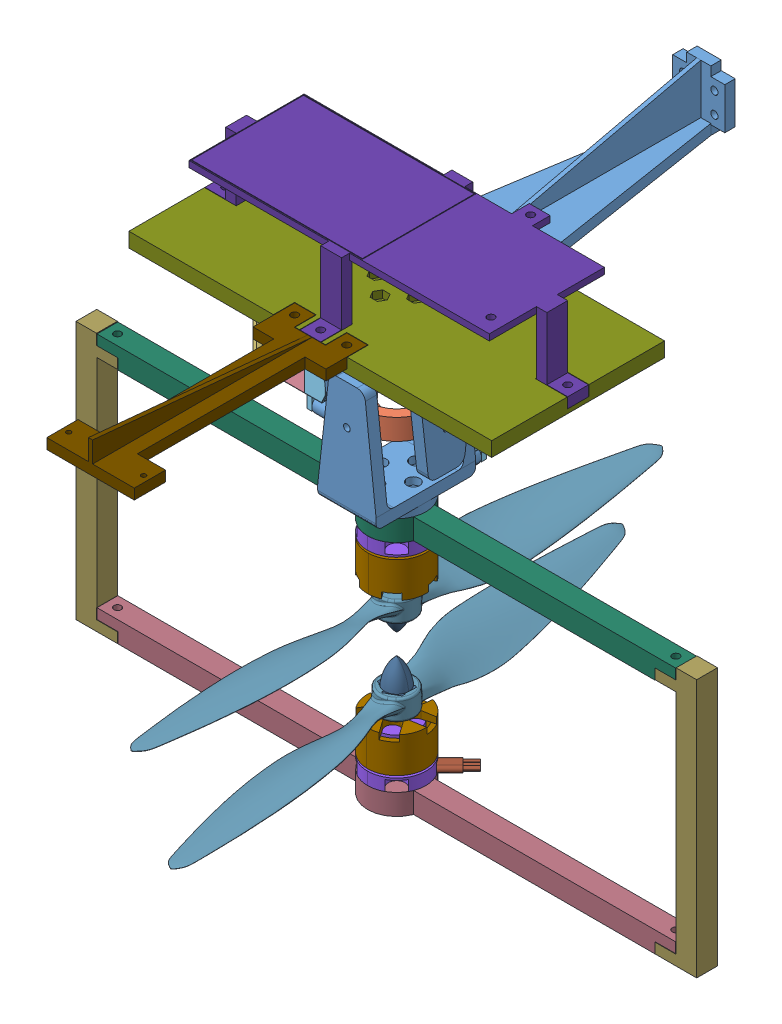
SolidWorks assembly Test Stand Assembly, configuration Default. Lengths in mm.
Overall size (298 240.68 297).
43 component instances, 19 part files, 15 mates.
Components (placement in the parent):
- Gimbal Sub-Assembly-2: Gimbal Sub-Assembly [Default] at (28.745 72.6035 97.1002) x (1 0 0) z (0 0 -1) size (84.83 79.88 84.83)
  - Gimbal Mount-2: Gimbal Mount [Default] at origin size (55.76 58.88 28)
  - Gimbal Ring-1: Gimbal Ring [Default] at (0 31 -14) x (-1 0 0) z (0 0 -1) size (39.86 10 39.86)
  - Gimbal Mount-5: Gimbal Mount [Default] at (-14 72 -14) x (0 0 -1) z (-1 0 0) size (55.76 58.88 28)
  - Servomotor SG 5010-1: Servomotor SG 5010 [Default] at (-54.2173 28.1066 -53.8759) x (0 -1 0) z (-0.008727 0 0.999962) size (54.4 42.11 20.33)
    - Tap 01-1: Tap 01 [Default] at (2.6095 0.3364 39.8745) x (1 0 0) z (0 -0.008727 -0.999962) size (41 6.5 20)
    - Tap 02-1: Tap 02 [Default] at (2.6095 20.3356 39.6999) x (1 0 0) z (0 -0.008727 -0.999962) size (41 20 20)
    - Tap 03-1: Tap 03 [Default] at (2.6095 20.3356 39.6999) x (-1 0 0) z (0 -0.008727 -0.999962) size (54.4 11.9 20)
    - Eje-1: Eje [Default] at (-7.8905 29.3353 39.6214) x (1 0 0) z (0 0.008727 0.999962) size (6 6.5 6)
    - pan head cross recess screw_iso-1: pan head cross recess screw_iso [ISO 7045 - M1.6 x 16 - Z - 16C] at (-15.5814 -5.9305 32.238) x (0 0.999962 -0.008727) z (0.720061 0.006055 0.693884) size (17.27 3.2 3.2)
    - pan head cross recess screw_iso-2: pan head cross recess screw_iso [ISO 7045 - M1.6 x 16 - Z - 16C] at (-15.5814 -5.7963 47.6192) x (0 0.999962 -0.008727) z (0.008727 0.008726 0.999924) size (17.27 3.2 3.2)
    - pan head cross recess screw_iso-3: pan head cross recess screw_iso [ISO 7045 - M1.6 x 16 - Z - 16C] at (20.8004 -5.7963 47.6192) x (0 0.999962 -0.008727) z (0.008727 0.008726 0.999924) size (17.27 3.2 3.2)
    - pan head cross recess screw_iso-4: pan head cross recess screw_iso [ISO 7045 - M1.6 x 16 - Z - 16C] at (20.8004 -5.9305 32.238) x (0 0.999962 -0.008727) z (0.008727 0.008726 0.999924) size (17.27 3.2 3.2)
  - Servomotor SG 5010-2: Servomotor SG 5010 [Default] at (39.8759 43.8934 40.2173) x (0 1 0) z (-0.999962 0 0.008727) size (54.4 42.11 20.33)
    - Tap 01-1: Tap 01 [Default] at (2.6095 0.3364 39.8745) x (1 0 0) z (0 -0.008727 -0.999962) size (41 6.5 20)
    - Tap 02-1: Tap 02 [Default] at (2.6095 20.3356 39.6999) x (1 0 0) z (0 -0.008727 -0.999962) size (41 20 20)
    - Tap 03-1: Tap 03 [Default] at (2.6095 20.3356 39.6999) x (-1 0 0) z (0 -0.008727 -0.999962) size (54.4 11.9 20)
    - Eje-1: Eje [Default] at (-7.8905 29.3353 39.6214) x (1 0 0) z (0 0.008727 0.999962) size (6 6.5 6)
    - pan head cross recess screw_iso-1: pan head cross recess screw_iso [ISO 7045 - M1.6 x 16 - Z - 16C] at (-15.5814 -5.9305 32.238) x (0 0.999962 -0.008727) z (0.720061 0.006055 0.693884) size (17.27 3.2 3.2)
    - pan head cross recess screw_iso-2: pan head cross recess screw_iso [ISO 7045 - M1.6 x 16 - Z - 16C] at (-15.5814 -5.7963 47.6192) x (0 0.999962 -0.008727) z (0.008727 0.008726 0.999924) size (17.27 3.2 3.2)
    - pan head cross recess screw_iso-3: pan head cross recess screw_iso [ISO 7045 - M1.6 x 16 - Z - 16C] at (20.8004 -5.7963 47.6192) x (0 0.999962 -0.008727) z (0.008727 0.008726 0.999924) size (17.27 3.2 3.2)
    - pan head cross recess screw_iso-4: pan head cross recess screw_iso [ISO 7045 - M1.6 x 16 - Z - 16C] at (20.8004 -5.9305 32.238) x (0 0.999962 -0.008727) z (0.008727 0.008726 0.999924) size (17.27 3.2 3.2)
- Motor Mount Sub-Assembly-1: Motor Mount Sub-Assembly [Default] at (25.1782 -3.1365 122.3263) x (1 0 0) z (0 0 -1) size (298 124 255.79)
  - User Library-emaxmodel-mt2213.STEP-1: User Library-emaxmodel-mt2213.STEP [Default] at (3.5668 10.2 11.2261) size (36.98 47 36.98)
    - emaxmodel-mt2213-stator_По умолчанию.STEP-1: emaxmodel-mt2213-stator_По умолчанию.STEP [Default] at origin size (28 21 28)
    - emaxmodel-mt2213-rotor_По умолчанию.STEP-1: emaxmodel-mt2213-rotor_По умолчанию.STEP [Default] at (0 7 0) x (0.999557 0 0.02976) z (-0.02976 0 0.999557) size (28 32 28)
    - emaxmodel-mt2213-cone_По умолчанию.STEP-1: emaxmodel-mt2213-cone_По умолчанию.STEP [Default] at (0 32 0) size (12 15 13.86)
    - wires_По умолчанию.STEP-1: wires_По умолчанию.STEP [Default] at (-15.8508 1.5 15.8508) x (0.707107 0 0.707107) z (-0.707107 0 0.707107) size (7 3 19)
  - Motor Mount Sides-1: Motor Mount Sides [Default] at (142.5668 0 16.2261) size (19.9 124 10)
  - Motor Mount Sides-3: Motor Mount Sides [Default] at (-135.4332 0 6.2261) x (-1 0 0) z (0 0 -1) size (19.9 124 10)
  - Motor Mount Lower-2: Motor Mount Lower [Default] at (3.5668 114 11.2261) size (277.8 10 28)
  - Propeller 10x45.step-1: Propeller 10x45.step [Default] at (3.5668 43.2 11.2261) size (28.85 11.2 254.24)
  - User Library-emaxmodel-mt2213.STEP-2: User Library-emaxmodel-mt2213.STEP [Default] at (3.5668 114 11.2261) x (-1 0 0) z (0 0 1) size (36.98 47 36.98)
    - emaxmodel-mt2213-stator_По умолчанию.STEP-1: emaxmodel-mt2213-stator_По умолчанию.STEP [Default] at origin size (28 21 28)
    - emaxmodel-mt2213-rotor_По умолчанию.STEP-1: emaxmodel-mt2213-rotor_По умолчанию.STEP [Default] at (0 7 0) x (0.999557 0 0.02976) z (-0.02976 0 0.999557) size (28 32 28)
    - emaxmodel-mt2213-cone_По умолчанию.STEP-1: emaxmodel-mt2213-cone_По умолчанию.STEP [Default] at (0 32 0) size (12 15 13.86)
    - wires_По умолчанию.STEP-1: wires_По умолчанию.STEP [Default] at (-15.8508 1.5 15.8508) x (0.707107 0 0.707107) z (-0.707107 0 0.707107) size (7 3 19)
  - Propeller 10x45.step-2: Propeller 10x45.step [Default] at (3.5668 84 11.2261) x (-0.990503 0 -0.137494) z (-0.137494 0 0.990503) size (28.85 11.2 254.24)
  - Motor Mount Upper-3: Motor Mount Upper [Default] at (3.5668 0.2 11.2261) size (277.8 10 28)
- Bottom Deck-1: Bottom Deck [Default] at (-58.34 76.5435 152.6002) size (174.17 7 83)
- Upper Deck-1: Upper Deck [Default] at (28.745 78.5435 111.1002) x (1 0 0) z (0 1 0) size (174.17 83 35)
- LIDAR Sensor Mount-1: LIDAR Sensor Mount [Default] at (49.745 78.5435 243.1002) x (-1 0 0) z (0 0 -1) size (42 15 115.5)
- Slider Mount-1: Slider Mount [Default] at (49.245 76.5435 -38.8998) x (-1 0 0) z (0 0 -1) size (41 28.9 118.5)
Mates (geometry in assembly coordinates):
- Concentric3: concentric aligned: cylinder of Gimbal Sub-Assembly-2/Gimbal Mount-2 through (38.245 62.1538 111.1002) axis (0 1 0) radius 1.75; cylinder of Bottom Deck-1 through (38.245 76.5435 111.1002) axis (0 1 0) radius 1.75
- Concentric4: concentric aligned: cylinder of Gimbal Sub-Assembly-2/Gimbal Mount-2 through (28.745 62.1538 119.1002) axis (0 1 0) radius 1.75; cylinder of Bottom Deck-1 through (28.745 76.5435 119.1002) axis (0 1 0) radius 1.75
- Coincident2: coincident anti-aligned: plane of Gimbal Sub-Assembly-2/Gimbal Mount-2 through (28.5461 76.5435 116.0002) normal (0 1 0); plane of Bottom Deck-1 through (-58.34 76.5435 152.6002) normal (0 -1 0)
- Concentric7: concentric aligned: cylinder of Bottom Deck-1 through (-53.34 76.5435 111.1002) axis (0 1 0) radius 1.75; cylinder of Upper Deck-1 through (-53.34 78.5435 111.1002) axis (0 1 0) radius 1.73
- Concentric8: concentric aligned: cylinder of Bottom Deck-1 through (28.745 76.5435 147.6002) axis (0 1 0) radius 1.75; cylinder of Upper Deck-1 through (28.745 78.5435 147.6002) axis (0 1 0) radius 1.73
- Coincident6: coincident anti-aligned: plane of Bottom Deck-1 through (-58.34 78.5435 152.6002) normal (0 1 0); plane of Upper Deck-1 through (28.745 78.5435 111.1002) normal (0 -1 0)
- Coincident7: coincident anti-aligned: plane of Bottom Deck-1 through (-58.34 78.5435 152.6002) normal (0 1 0); plane of LIDAR Sensor Mount-1 through (49.745 78.5435 243.1002) normal (0 -1 0)
- Concentric9: concentric aligned: cylinder of Bottom Deck-1 through (16.245 76.5435 147.6002) axis (0 1 0) radius 1.75; cylinder of LIDAR Sensor Mount-1 through (16.245 78.5435 147.6002) axis (0 1 0) radius 1.75
- Concentric10: concentric aligned: cylinder of Bottom Deck-1 through (41.245 76.5435 147.6002) axis (0 1 0) radius 1.75; cylinder of LIDAR Sensor Mount-1 through (41.245 78.5435 147.6002) axis (0 1 0) radius 1.75
- Coincident8: coincident anti-aligned: plane of Bottom Deck-1 through (-58.34 81.5435 152.6002) normal (0 -1 0); plane of Slider Mount-1 through (49.245 81.5435 -38.8998) normal (0 1 0)
- Concentric11: concentric anti-aligned: cylinder of Bottom Deck-1 through (44.245 83.5435 74.6002) axis (0 -1 0) radius 1.75; cylinder of Slider Mount-1 through (44.245 76.5435 74.6002) axis (0 1 0) radius 1.75
- Concentric13: concentric anti-aligned: cylinder of Bottom Deck-1 through (13.245 83.5435 74.6002) axis (0 -1 0) radius 1.75; cylinder of Slider Mount-1 through (13.245 76.5435 74.6002) axis (0 1 0) radius 1.75
- Concentric14: concentric: cylinder of Gimbal Sub-Assembly-2/Gimbal Mount-5 through (20.745 11.0532 111.1002) axis (0 -1 0) radius 1.75; cylinder of Motor Mount Sub-Assembly-1/Motor Mount Upper-3 through (20.745 -3.3365 111.1002) axis (0 -1 0) radius 1.75
- Concentric15: concentric: cylinder of Gimbal Sub-Assembly-2/Gimbal Mount-5 through (28.745 11.0532 120.6002) axis (0 -1 0) radius 1.75; cylinder of Motor Mount Sub-Assembly-1/Motor Mount Upper-3 through (28.745 -3.3365 120.6002) axis (0 -1 0) radius 1.75
- Coincident9: coincident anti-aligned: plane of Gimbal Sub-Assembly-2/Gimbal Mount-5 through (33.645 -3.3365 110.9012) normal (0 -1 0); plane of Motor Mount Sub-Assembly-1/Motor Mount Upper-3 through (28.745 -3.3365 111.1002) normal (0 1 0)
